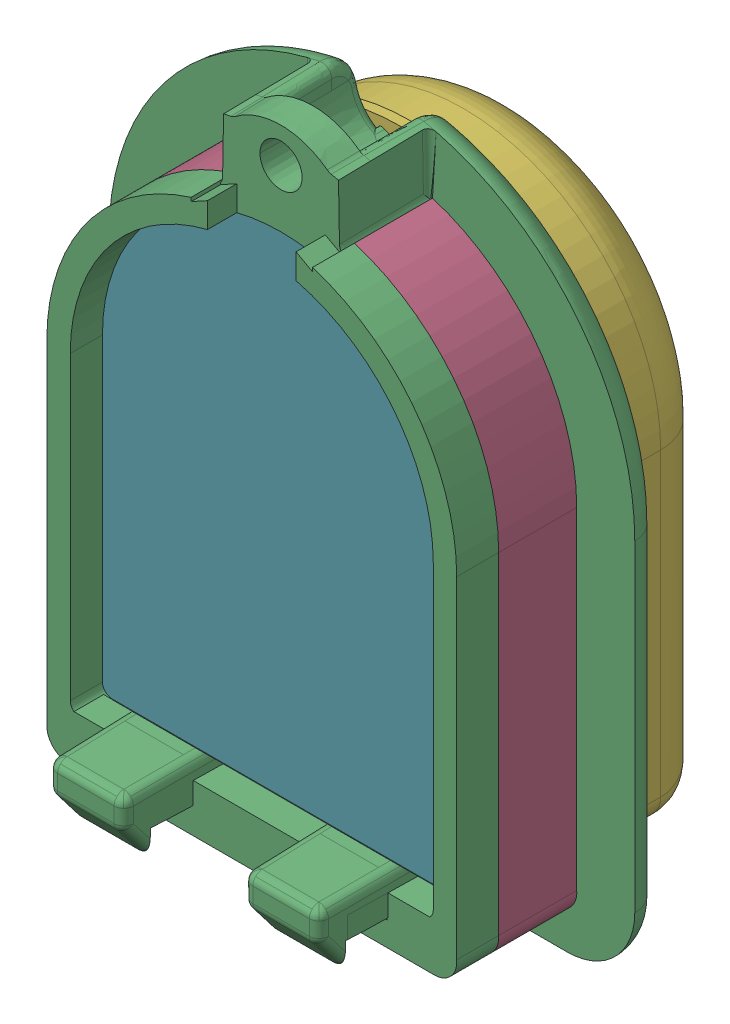
SolidWorks assembly Body, configuration 默认. Lengths in mm.
Overall size (26.95 34.26 17.16).
5 component instances, 5 part files, 12 mates.
Components (placement in the parent):
- OriginBody-1: OriginBody [默认] at (-2.213 7.3799 -8.324) size (26.95 34.26 11.18)
- 实体3-1: 实体3 [默认] at (-2.213 7.3799 -8.324) size (21.01 28.27 4)
- NewInsideSkin-1: NewInsideSkin [默认] at (-2.213 4.0799 -8.324) x (-1 0 0) z (0 0 -1) size (18.6 25.2 5.2)
- outSkin-1: outSkin [默认] at (-2.213 4.0799 -8.324) x (-1 0 0) z (0 0 -1) size (21.8 28.4 6)
- NewBoardlensnew-1: NewBoardlensnew [默认] at (-2.213 7.3799 -8.324) size (18.6 25.2 6)
Mates (geometry in assembly coordinates):
- 重合1: coincident anti-aligned: plane of OriginBody-1 through (-2.213 7.3799 -6.824) normal (0 0 1); plane of 实体3-1 through (7.137 -9.7124 -6.824) normal (0 0 -1)
- 同心1: concentric aligned: cylinder of OriginBody-1 through (-2.213 7.3799 -0.674) axis (0 0 -1) radius 10.5; cylinder of 实体3-1 through (-2.213 7.3799 -0.674) axis (0 0 -1) radius 10.5
- 重合2: coincident aligned: plane of OriginBody-1 through (8.287 7.3799 -0.674) normal (1 0 0); plane of 实体3-1 through (8.287 7.3799 -0.674) normal (1 0 0)
- 重合3: coincident anti-aligned: plane of 实体3-1 through (-2.213 -8.5201 48.523) normal (0 1 0); plane of NewBoardlensnew-1 through (-11.513 -8.5201 -2.324) normal (0 -1 0)
- 同心2: concentric aligned: cylinder of 实体3-1 through (-2.213 7.3799 48.523) axis (0 0 -1) radius 9.3; cylinder of NewBoardlensnew-1 through (-2.213 7.3799 -2.324) axis (0 0 -1) radius 9.3
- 重合4: coincident aligned: plane of OriginBody-1 through (-2.2735 3.9424 -8.324) normal (0 0 -1); plane of NewBoardlensnew-1 through (-2.213 7.3799 -8.324) normal (0 0 -1)
- 重合5: coincident anti-aligned: plane of NewInsideSkin-1 through (-11.013 -8.0201 -8.324) normal (0 0 1); plane of NewBoardlensnew-1 through (-2.213 7.3799 -8.324) normal (0 0 -1)
- 平行1: parallel anti-aligned: line of OriginBody-1 through (-11.513 7.3799 -8.324) axis (0 -1 0); line of NewInsideSkin-1 through (-11.513 -8.0201 -8.324) axis (0 1 0)
- 同心3: concentric anti-aligned: circle of OriginBody-1; circle of NewInsideSkin-1
- 重合6: coincident anti-aligned: plane of NewInsideSkin-1 through (-11.013 -8.0201 -13.524) normal (0 0 -1); plane of outSkin-1 through (-11.013 -8.0201 -13.524) normal (0 0 1)
- 同心4: concentric aligned: cylinder of NewInsideSkin-1 through (-2.213 7.3799 -13.524) axis (0 0 1) radius 9.3; cylinder of outSkin-1 through (-2.213 7.3799 -13.524) axis (0 0 1) radius 9.3
- 平行2: parallel aligned: plane of NewInsideSkin-1 through (-11.013 -8.5201 -13.524) normal (0 -1 0); plane of outSkin-1 through (-11.013 -9.3201 -13.524) normal (0 -1 0)
